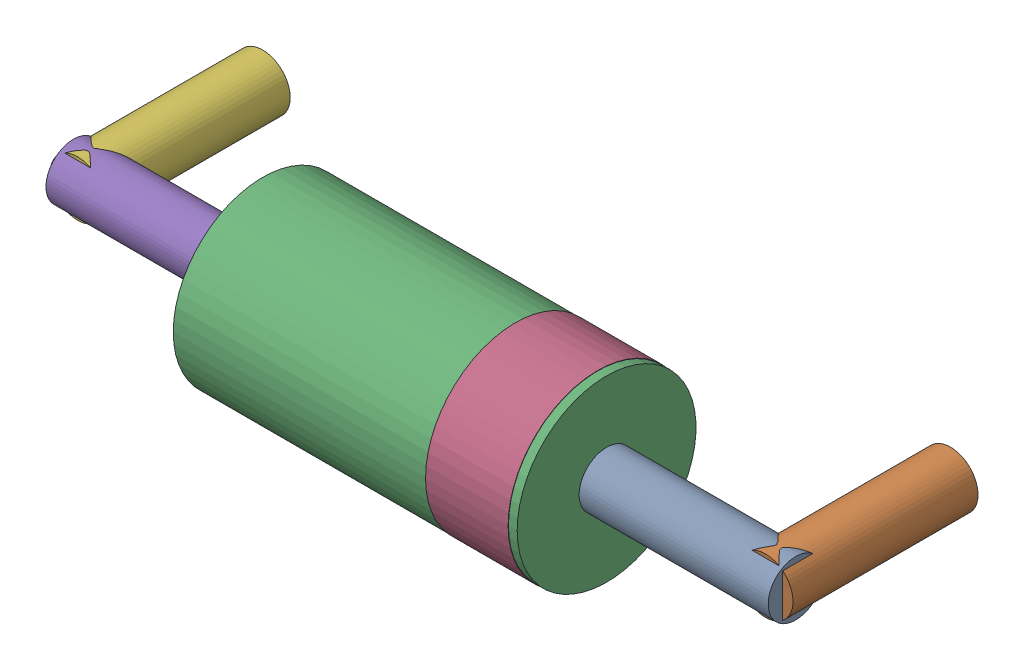
SolidWorks assembly D1, configuration Default. Lengths in mm.
Overall size (10.8 2.61 3.81).
12 component instances, 6 part files, 0 mates.
Components (placement in the parent):
- -1733042672-1: -1733042672 [Default] at (514.1494 293.1651 1.5) x (0 0 -1) z (-1 0 0) size (0.8 0.8 2.75)
  - Cylinder-1: Cylinder [Default] at origin size (0.8 0.8 2.75)
- -1733042992-1: -1733042992 [Default] at (513.8991 293.1673 -1) x (-1 0 0) z (0 0 1) size (0.8 0.8 2.69)
  - Cylinder_2-1: Cylinder_2 [Default] at origin size (0.8 0.8 2.69)
- -1733042432-1: -1733042432 [Default] at (511.3992 293.1649 1.5) x (0 0 -1) z (-1 0 0) size (2.6 2.6 5)
  - Cylinder_3-1: Cylinder_3 [Default] at origin size (2.6 2.6 5)
- -1733042152-1: -1733042152 [Default] at (511.2722 293.1649 1.5) x (0 0 -1) z (-1 0 0) size (2.61 2.61 1.2)
  - Cylinder_4-1: Cylinder_4 [Default] at origin size (2.61 2.61 1.2)
- -1733041072-1: -1733041072 [Default] at (503.6489 293.1697 1.5) x (0 0 -1) z (1 0 0) size (0.8 0.8 2.75)
  - Cylinder_5-1: Cylinder_5 [Default] at origin size (0.8 0.8 2.75)
- -1733041192-1: -1733041192 [Default] at (503.8992 293.1675 -1) x (1 0 0) z (0 0 1) size (0.8 0.8 2.69)
  - Cylinder_6-1: Cylinder_6 [Default] at origin size (0.8 0.8 2.69)
